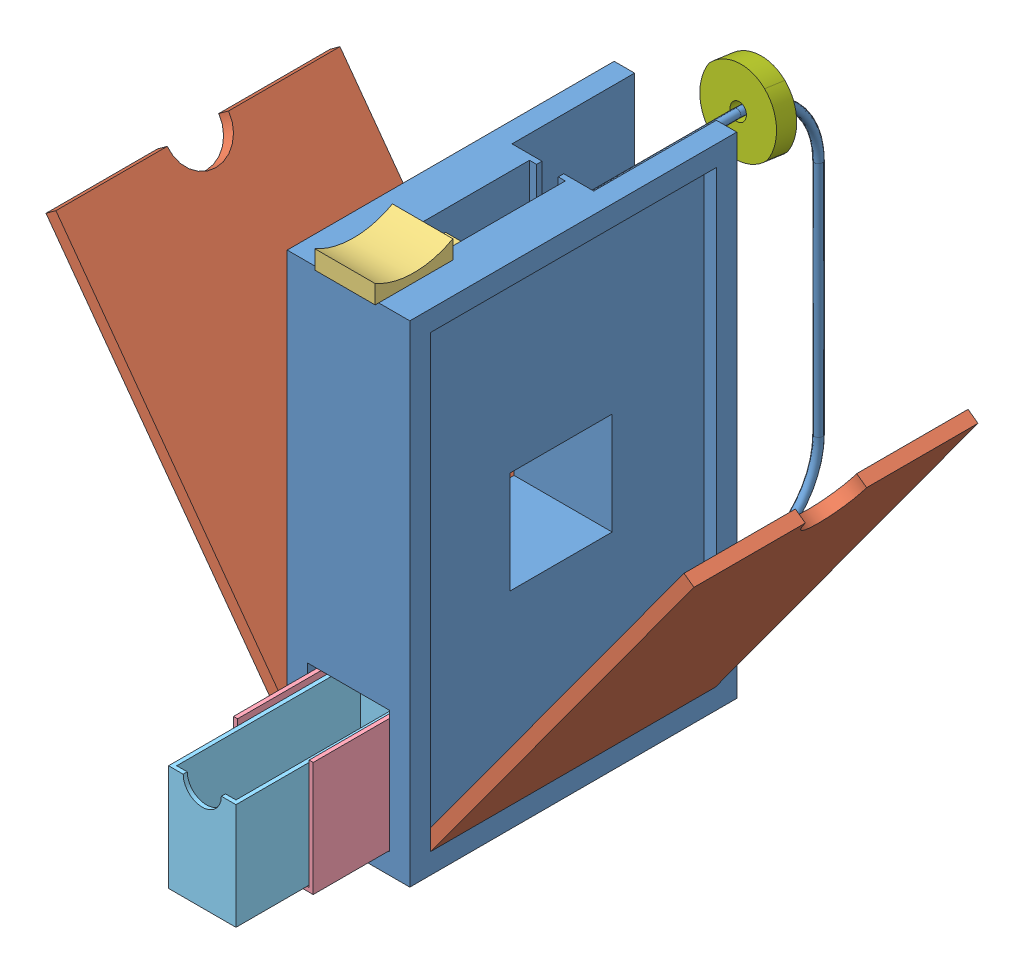
SolidWorks assembly lec37-practice, configuration Default. Lengths in mm.
Overall size (159.07 129.22 151.79).
8 component instances, 7 part files, 15 mates.
Components (placement in the parent):
- Main body^lec37-practice-1: Main body^lec37-practice [Default] x (0 0 -1) z (1 0 0) size (116 120 30) (virtual)
- Side cover^lec37-practice-1: Side cover^lec37-practice [Default] at (-8.7015 29.7775 0) x (-0.389902 -0.920856 0) z (0 0 1) size (106.81 27.77 69.5) (virtual)
- Knocker^lec37-practice-1: Knocker^lec37-practice [Default] at (0 60 1.6012) x (0 0 -1) z (0 1 0) size (27 14.77 24.53) (virtual)
- Slider^lec37-practice-2: Slider^lec37-practice [Default] at (-0.0179 -1.3392 10.3932) size (19.5 28 48) (virtual)
- Drawer^lec37-practice-1: Drawer^lec37-practice [Default] at (-0.1525 -1.5025 28.7864) size (16.5 26 47) (virtual)
- Touch Pad^lec37-practice-1: Touch Pad^lec37-practice [Default] at (-6.4429 -23.7803 40) x (-1 0 0) z (0 0 -1) size (17 35 1) (virtual)
- Bead^lec37-practice-1: Bead^lec37-practice [Default] at (0 48.8009 -57.8152) x (0.606512 0.787159 -0.111913) z (0 -0.140758 -0.990044) size (18 19.9 5) (virtual)
- Side cover^lec37-practice-4: Side cover^lec37-practice [Default] at (8.7015 29.7775 0) x (0.389902 -0.920856 0) z (0 0 -1) size (106.81 27.77 69.5) (virtual)
Mates (geometry in assembly coordinates):
- Coincident1: coincident anti-aligned: line of Main body^lec37-practice-1 through (15 -55 35) axis (0 0 -1); line of Side cover^lec37-practice-1 through (15 -55 -34.75) axis (0 0 1)
- Width1: width anti-aligned: plane of Main body^lec37-practice-1 through (12 55 35) normal (0 0 -1); plane of Side cover^lec37-practice-1 through (12 -55 -35) normal (0 0 1); plane of Main body^lec37-practice-1 through (76.8433 34.8076 34.75) normal (0 0 1); plane of Side cover^lec37-practice-1 through (76.8433 34.8076 -34.75) normal (0 0 -1)
- LimitAngle1: limit planar angle = 0.630564 rad anti-aligned: plane of Main body^lec37-practice-1 through (12 0 0) normal (1 0 0); plane of Side cover^lec37-practice-1 through (44.7101 -9.2118 0) normal (-0.807695 0.5896 0)
- Coincident3: coincident anti-aligned: plane of Main body^lec37-practice-1 through (15 60 40) normal (0 1 0); plane of Knocker^lec37-practice-1 through (0 60 1.6012) normal (0 -1 0)
- Width4: width anti-aligned: plane of Main body^lec37-practice-1 through (4.3837 -9.6833 -10) normal (-1 0 0); plane of Knocker^lec37-practice-1 through (-4.3837 -9.6833 -10) normal (1 0 0); plane of Main body^lec37-practice-1 through (3.3837 40 36.8703) normal (1 0 0); plane of Knocker^lec37-practice-1 through (-3.3837 40 36.8703) normal (-1 0 0)
- Width5: width aligned: plane of Main body^lec37-practice-1 through (-4.3837 -500000 -8.6641) normal (0 0 1); plane of Knocker^lec37-practice-1 through (4.3837 -9.6833 36.8703) normal (0 0 -1); plane of Main body^lec37-practice-1 through (-3.3837 40 36.8703) normal (0 0 1); plane of Knocker^lec37-practice-1 through (-3.3837 40 21.8703) normal (0 0 -1)
- Coincident4: coincident anti-aligned: plane of Main body^lec37-practice-1 through (-10 -55 -46.0555) normal (0 1 0); plane of Slider^lec37-practice-2 through (-9.75 -55 58.3932) normal (0 -1 0)
- Coincident5: coincident anti-aligned: plane of Slider^lec37-practice-2 through (-9.75 -54 58.3932) normal (0 1 0); plane of Drawer^lec37-practice-1 through (-8.25 -54 75.7864) normal (0 -1 0)
- Width6: width anti-aligned: plane of Main body^lec37-practice-1 through (-10 -55 -46.0555) normal (1 0 0); plane of Slider^lec37-practice-2 through (10 -55 -46.0555) normal (-1 0 0); plane of Main body^lec37-practice-1 through (-9.75 -55 58.3932) normal (-1 0 0); plane of Slider^lec37-practice-2 through (9.75 -55 58.3932) normal (1 0 0)
- Width7: width anti-aligned: plane of Slider^lec37-practice-2 through (-8.75 -55 58.3932) normal (1 0 0); plane of Drawer^lec37-practice-1 through (8.75 -55 58.3932) normal (-1 0 0); plane of Slider^lec37-practice-2 through (-8.25 -54 75.7864) normal (-1 0 0); plane of Drawer^lec37-practice-1 through (8.25 -54 75.7864) normal (1 0 0)
- LimitDistance1: limit distance = 18.3932 mm anti-aligned: plane of Main body^lec37-practice-1 through (0 0 -8) normal (0 0 1); plane of Slider^lec37-practice-2 through (-0.0179 -1.3392 10.3932) normal (0 0 -1)
- LimitDistance2: limit distance = 36.7864 mm anti-aligned: plane of Main body^lec37-practice-1 through (0 0 -8) normal (0 0 1); plane of Drawer^lec37-practice-1 through (-0.1525 -1.5025 28.7864) normal (0 0 -1)
- Linear/Linear Coupler1: linear coupler = 2 : 1 mm: plane of Drawer^lec37-practice-1 through (-0.1525 -1.5025 75.7864) normal (0 0 1); plane of Slider^lec37-practice-2 through (-0.0179 -1.3392 58.3932) normal (0 0 1)
- ProfileCenter1: profile center = 0 mm aligned: plane of Main body^lec37-practice-1 through (15 -60 40) normal (0 0 1); plane of Touch Pad^lec37-practice-1 through (-6.4429 -23.7803 40) normal (0 0 1)
- PathMate1: path: point of Bead^lec37-practice-1; curve of Main body^lec37-practice-1
